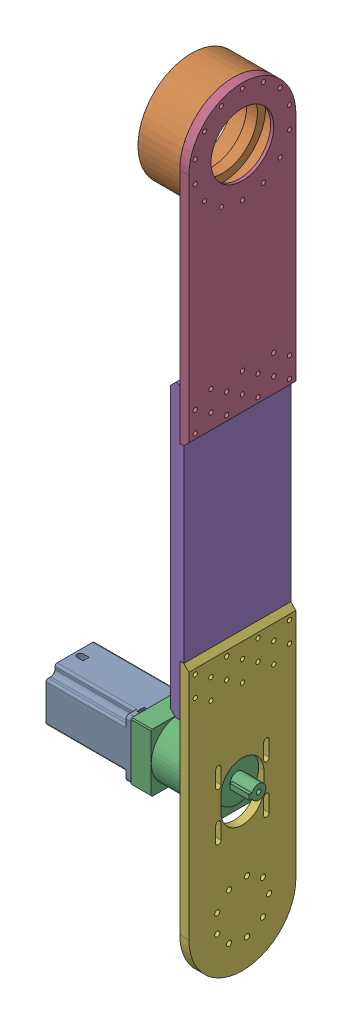
SolidWorks assembly arm_manipulator_link_2, configuration Default. Lengths in mm.
Overall size (181 755 105).
6 component instances, 6 part files, 15 mates.
Components (placement in the parent):
- Nema2323HS8328_1-3: Nema2323HS8328_1 [Default] at (-79.4 -169.5827 -52.52) x (0 0 1) z (-1 0 0) size (56.4 56.4 105.78)
- J3SpindleHousing_1-1: J3SpindleHousing_1 [Default] at (-29.5 372.8973 -52.5) x (1 0 0) z (0 -1 0) size (41 105 105)
- PlanetaryGearboxNEMA23_PX57004_SKU030_1-10: PlanetaryGearboxNEMA23_PX57004_SKU030_1 [Default] at (-5 -169.6027 -52.5) x (0 1 0) z (-1 0 0) size (57 57 97)
- J2BottomArmB_1-1: J2BottomArmB_1 [Default] at (-4.5 -277.1027 -52.5) x (1 0 0) z (0 1 0) size (9 105 285)
- J2BottomArmC_1-1: J2BottomArmC_1 [Default] at (-4.5 -277.1027 -52.5) x (1 0 0) z (0 1 0) size (13 105 285)
- J2BottomArmA_1-1: J2BottomArmA_1 [Default] at (-4.5 -277.1027 -52.5) x (1 0 0) z (0 1 0) size (9 105 285)
Mates (geometry in assembly coordinates):
- Concentric56: concentric aligned: circle of Nema2323HS8328_1-3; circle of PlanetaryGearboxNEMA23_PX57004_SKU030_1-10
- Parallel7: parallel aligned: plane of Nema2323HS8328_1-3 through (-85.7545 -141.3827 -52.52) normal (0 1 0); plane of PlanetaryGearboxNEMA23_PX57004_SKU030_1-10 through (-19 -141.1027 -81) normal (0 1 0)
- Coincident49: coincident anti-aligned: plane of Nema2323HS8328_1-3 through (-81 -169.5827 -52.52) normal (1 0 0); plane of PlanetaryGearboxNEMA23_PX57004_SKU030_1-10 through (-81 -169.6027 -52.5) normal (-1 0 0)
- Concentric140: concentric aligned: cylinder of J2BottomArmB_1-1 through (0 150.3973 -6.25) axis (-1 0 0) radius 2.1; cylinder of J2BottomArmC_1-1 through (744.4889 150.3973 -6.25) axis (-1 0 0) radius 2.5125
- Concentric141: concentric aligned: cylinder of J2BottomArmB_1-1 through (0 170.3973 -98.75) axis (-1 0 0) radius 2.1; cylinder of J2BottomArmC_1-1 through (744.4889 170.3973 -98.75) axis (-1 0 0) radius 2.5125
- Coincident95: coincident anti-aligned: plane of J2BottomArmB_1-1 through (-9 47.8973 -52.5) normal (-1 0 0); plane of J2BottomArmC_1-1 through (-9 47.8973 -52.5) normal (1 0 0)
- Concentric163: concentric aligned: cylinder of J2BottomArmC_1-1 through (744.4889 -54.6027 -98.75) axis (-1 0 0) radius 2.5125; cylinder of J2BottomArmA_1-1 through (0 -54.6027 -98.75) axis (-1 0 0) radius 2.1
- Concentric164: concentric aligned: cylinder of J2BottomArmC_1-1 through (744.4889 -54.6027 -6.25) axis (-1 0 0) radius 2.5125; cylinder of J2BottomArmA_1-1 through (0 -54.6027 -6.25) axis (-1 0 0) radius 2.1
- Coincident107: coincident anti-aligned: plane of J2BottomArmC_1-1 through (-9 47.8973 -52.5) normal (1 0 0); plane of J2BottomArmA_1-1 through (-9 47.8973 -52.5) normal (-1 0 0)
- Concentric166: concentric anti-aligned: cylinder of PlanetaryGearboxNEMA23_PX57004_SKU030_1-10 through (-13.5 -146.0327 -28.93) axis (1 0 0) radius 2.75; cylinder of J2BottomArmA_1-1 through (753.3295 -146.0327 -28.93) axis (-1 0 0) radius 2.65
- Coincident109: coincident anti-aligned: plane of PlanetaryGearboxNEMA23_PX57004_SKU030_1-10 through (-8 -169.6027 -52.5) normal (1 0 0); plane of J2BottomArmA_1-1 through (-8 47.8973 -52.5) normal (-1 0 0)
- Parallel19: parallel aligned: plane of PlanetaryGearboxNEMA23_PX57004_SKU030_1-10 through (-19 -198.1027 -81) normal (0 0 -1); plane of J2BottomArmA_1-1 through (0 -185.8527 -105) normal (0 0 -1)
- Concentric167: concentric anti-aligned: cylinder of J3SpindleHousing_1-1 through (-29 415.6934 -73.1095) axis (1 0 0) radius 1.65; cylinder of J2BottomArmB_1-1 through (0 415.6934 -73.1095) axis (-1 0 0) radius 2.025
- Concentric168: concentric aligned: cylinder of J3SpindleHousing_1-1 through (-21.25 372.8973 -52.5) axis (-1 0 0) radius 34.5121; cylinder of J2BottomArmB_1-1 through (0 372.8973 -52.5) axis (-1 0 0) radius 30.796
- Coincident110: coincident anti-aligned: plane of J3SpindleHousing_1-1 through (-9 372.8973 -52.5) normal (1 0 0); plane of J2BottomArmB_1-1 through (-9 47.8973 -52.5) normal (-1 0 0)
